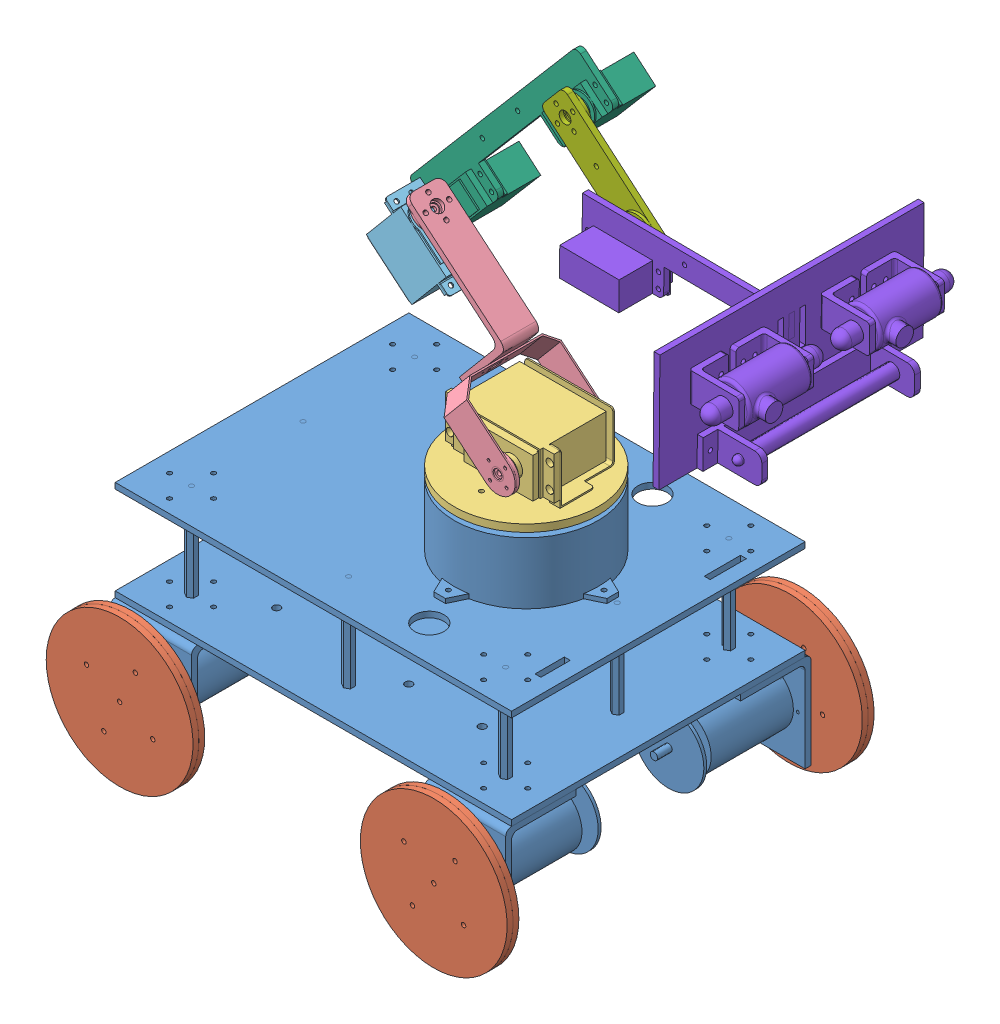
SolidWorks assembly exa_robot_part, configuration Default. Lengths in mm.
Overall size (452.74 461.66 342.18).
11 component instances, 8 part files, 26 mates.
Components (placement in the parent):
- base_robot-1: base_robot [Default] at (14.2374 -23.114 -6.4589) size (270 179.13 234)
- roda_robot_fix-1: roda_robot_fix [Default] at (268.1239 -5.9891 251.6556) x (0.408711 0.912664 0) z (0 0 1) size (100 100 21)
- roda_robot_fix-2: roda_robot_fix [Default] at (-22.1829 120.8673 251.6556) x (-0.2415 -0.970401 0) z (0 0 1) size (100 100 21)
- roda_robot_fix-3: roda_robot_fix [Default] at (-43.3679 96.894 162.7099) x (0.933321 0.359042 0) z (0 0 -1) size (100 100 21)
- roda_robot_fix-4: roda_robot_fix [Default] at (229.5868 134.8934 162.7099) x (0.816348 -0.57756 0) z (0 0 -1) size (100 100 21)
- link1_robot-1: link1_robot [Default] at (14.2374 -23.114 -6.4589) size (98 43 98)
- link2_robot-1: link2_robot [Default] at (14.2374 -23.114 -6.4589) size (99.47 123.93 66)
- link3_robot-1: link3_robot [Default] at (14.2374 -23.114 -6.4589) size (56.44 54.96 29)
- link4_robot-1: link4_robot [Default] at (11.4345 -22.4006 -6.4589) x (0.999966 -0.008267 0) z (0 0 1) size (137.73 155 42.35)
- link5_robot-1: link5_robot [Default] at (11.4345 -22.4006 -6.4589) x (0.999966 -0.008267 0) z (0 0 1) size (81.1 72.97 14)
- link6_eof_robot-1: link6_eof_robot [Default] at (11.4345 -22.4006 -6.4589) x (0.999966 -0.008267 0) z (0 0 1) size (184.63 80 180)
Mates (geometry in assembly coordinates):
- Coincident1: coincident anti-aligned: plane of base_robot-1 through (258.5015 16.6149 311.1827) normal (0 0 1); plane of roda_robot_fix-1 through (235.6028 60.827 311.1827) normal (0 0 -1)
- Concentric1: concentric aligned: cylinder of base_robot-1 through (235.6028 60.827 324.1827) axis (0 0 -1) radius 2.5; cylinder of roda_robot_fix-1 through (235.6028 60.827 324.1827) axis (0 0 -1) radius 2.5
- Concentric2: concentric aligned: cylinder of base_robot-1 through (235.6028 60.827 90.1827) axis (0 0 1) radius 2.5; cylinder of roda_robot_fix-4 through (235.6028 60.827 90.1827) axis (0 0 1) radius 2.5
- Coincident3: coincident anti-aligned: plane of base_robot-1 through (212.704 16.6149 103.1827) normal (0 0 -1); plane of roda_robot_fix-4 through (235.6028 60.827 103.1827) normal (0 0 1)
- Coincident4: coincident anti-aligned: plane of base_robot-1 through (-1.296 105.0391 311.1827) normal (0 0 1); plane of roda_robot_fix-2 through (21.6028 60.827 311.1827) normal (0 0 -1)
- Concentric3: concentric aligned: cylinder of base_robot-1 through (21.6028 60.827 324.1827) axis (0 0 -1) radius 2.5; cylinder of roda_robot_fix-2 through (21.6028 60.827 324.1827) axis (0 0 -1) radius 2.5
- Coincident5: coincident anti-aligned: plane of base_robot-1 through (-1.296 16.6149 103.1827) normal (0 0 -1); plane of roda_robot_fix-3 through (21.6028 60.827 103.1827) normal (0 0 1)
- Concentric4: concentric aligned: cylinder of base_robot-1 through (21.6028 60.827 90.1827) axis (0 0 1) radius 2.5; cylinder of roda_robot_fix-3 through (21.6028 60.827 90.1827) axis (0 0 1) radius 2.5
- Coincident6: coincident anti-aligned: plane of base_robot-1 through (183.8898 208.9523 217.0887) normal (0 1 0); plane of link1_robot-1 through (173.6028 208.9523 207.1827) normal (0 -1 0)
- Concentric5: concentric aligned: cylinder of base_robot-1 through (173.6028 189.6967 207.1827) axis (0 1 0) radius 2.8131; cylinder of link1_robot-1 through (173.6028 204.9523 207.1827) axis (0 1 0) radius 3
- Coincident7: coincident anti-aligned: plane of link1_robot-1 through (189.1028 233.9523 239.1727) normal (0 0 1); plane of link2_robot-1 through (189.1028 233.9523 239.1727) normal (0 0 -1)
- Concentric6: concentric anti-aligned: cylinder of link1_robot-1 through (189.1028 233.9523 239.1727) axis (0 0 -1) radius 3; cylinder of link2_robot-1 through (189.1028 233.9523 236.1727) axis (0 0 1) radius 3
- Concentric7: concentric anti-aligned: cylinder of link2_robot-1 through (108.8974 331.277 208.7585) axis (0.642788 0.766044 0) radius 3; cylinder of link3_robot-1 through (110.8257 333.5751 208.7585) axis (-0.642788 -0.766044 0) radius 2.9972
- Coincident9: coincident anti-aligned: plane of link2_robot-1 through (110.8257 333.5751 208.7585) normal (-0.642788 -0.766044 0); plane of link3_robot-1 through (110.8257 333.5751 208.7585) normal (0.642788 0.766044 0)
- Coincident10: coincident anti-aligned: plane of link3_robot-1 through (99.1297 316.2635 192.7915) normal (0 0 -1); plane of link4_robot-1 through (99.1297 316.2635 192.7915) normal (0 0 1)
- Concentric8: concentric anti-aligned: cylinder of link3_robot-1 through (99.1297 316.2635 189.7915) axis (0 0 1) radius 3; cylinder of link4_robot-1 through (99.1297 316.2635 192.7915) axis (0 0 -1) radius 2.9972
- Coincident11: coincident anti-aligned: plane of link4_robot-1 through (191.6635 423.9248 192.7915) normal (0 0 1); plane of link5_robot-1 through (191.6635 423.9248 192.7915) normal (0 0 -1)
- Concentric9: concentric anti-aligned: cylinder of link4_robot-1 through (191.6635 423.9248 192.7915) axis (0 0 -1) radius 2.9972; cylinder of link5_robot-1 through (191.6635 423.9248 189.7915) axis (0 0 1) radius 3
- Coincident12: coincident anti-aligned: plane of link5_robot-1 through (241.87 381.0843 200.7915) normal (0 0 1); plane of link6_eof_robot-1 through (241.87 381.0843 200.7915) normal (0 0 -1)
- Concentric10: concentric anti-aligned: cylinder of link5_robot-1 through (241.87 381.0843 203.7915) axis (0 0 -1) radius 3; cylinder of link6_eof_robot-1 through (241.87 381.0843 200.7915) axis (0 0 1) radius 2.9972
- LimitAngle1: limit planar angle = 2.443461 rad anti-aligned: plane of link1_robot-1 through (173.6028 213.9523 207.1827) normal (0 1 0); plane of link2_robot-1 through (166.9546 268.2017 195.8793) normal (0.642788 0.766044 0)
- LimitAngle2: limit planar angle = 1.570796 rad anti-aligned: plane of link3_robot-1 through (93.6106 327.8772 218.7915) normal (-0.766044 0.642788 0); plane of link2_robot-1 through (109.4871 290.3828 220.7585) normal (0 0 1)
- LimitAngle3: limit planar angle = 1.562529 rad aligned: plane of link4_robot-1 through (100.5792 302.5054 177.361) normal (-0.649099 -0.760704 0); plane of link3_robot-1 through (93.6106 327.8772 218.7915) normal (-0.766044 0.642788 0)
- LimitAngle4: limit planar angle = 0 rad aligned: plane of link4_robot-1 through (190.214 437.683 177.361) normal (0.649099 0.760704 0); plane of link5_robot-1 through (190.3243 440.8425 198.7915) normal (0.649099 0.760704 0)
- LimitAngle5: limit planar angle = 2.268928 rad anti-aligned: plane of link5_robot-1 through (174.7459 422.5856 198.7915) normal (-0.649099 -0.760704 0); plane of link6_eof_robot-1 through (224.6686 374.3358 216.222) normal (-0.999966 0.008267 0)
- LimitAngle9: limit planar angle = 1.570796 rad anti-aligned: plane of link1_robot-1 through (203.1028 247.9523 225.1827) normal (1 0 0); plane of base_robot-1 through (200.3661 159.827 307.1827) normal (0 0 1)
